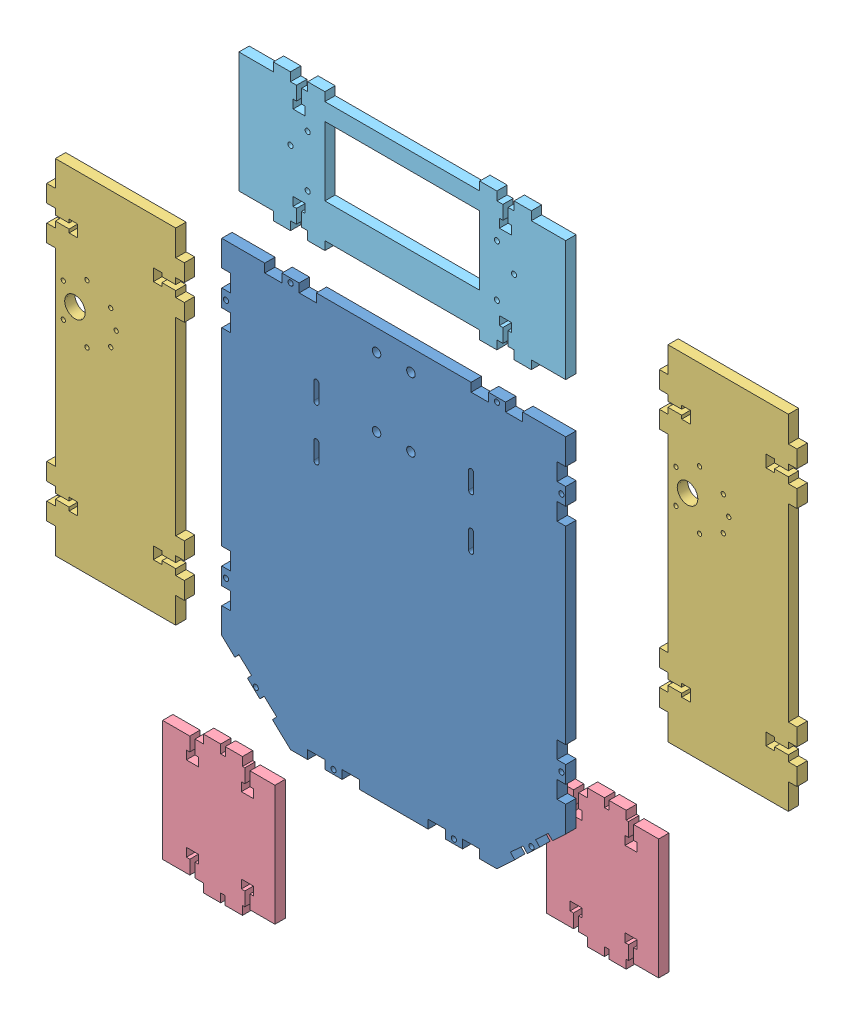
SolidWorks assembly Montagem2, configuration Valor predeterminado. Lengths in mm.
Overall size (355.08 524.73 168.73).
7 component instances, 5 part files, 0 mates.
Components (placement in the parent):
- chassi-1: chassi [Valor predeterminado] at (112.0239 130.1265 -3) size (200 237.5 6)
- frente-1: frente [Valor predeterminado] at (-20.0747 -59.8979 -82.9393) size (80 120 6)
- lateral-1: lateral [Valor predeterminado] at (122.7326 157.5276 -51.7161) size (80 200 6)
- lateral-2: lateral [Valor predeterminado] at (-152.3461 154.2939 29.3747) size (80 200 6)
- latFront-1: latFront [Valor predeterminado] at (129.2634 -152.1173 -39.8097) size (65.33 80 6)
- latFront-2: latFront [Valor predeterminado] at (-60.2414 -203.0151 -6.2113) size (65.33 80 6)
- traseira-1: traseira [Valor predeterminado] at (4.7861 311.7176 79.7938) size (190 80 6)
